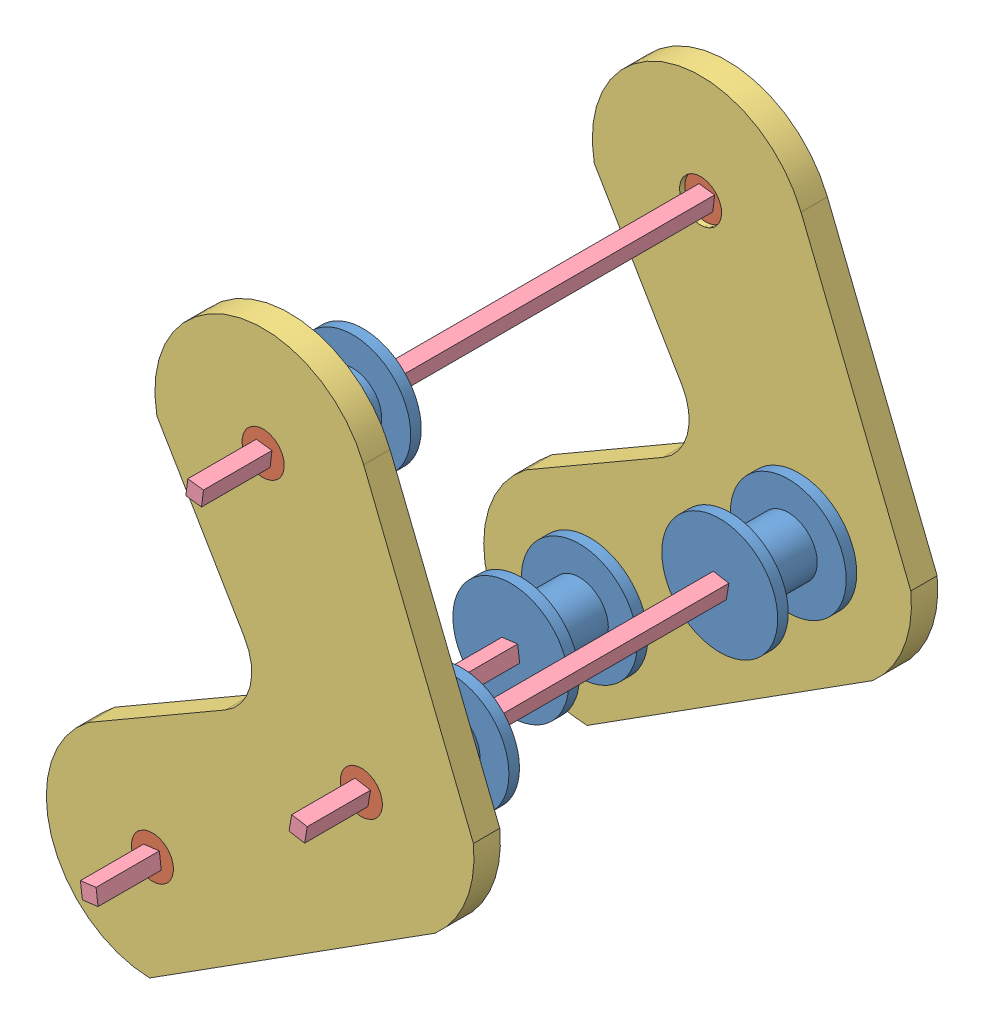
SolidWorks assembly intaker_assemble_new_20241129, configuration 默认. Lengths in mm.
Overall size (105.46 125.93 101).
15 component instances, 4 part files, 37 mates.
Components (placement in the parent):
- pulley_metal_20241129-1: pulley_metal_20241129 [默认] at (-0.8886 -0.165 14.4853) size (21.99 21.99 15)
- falon_metal_20241129-1: falon_metal_20241129 [默认] at (-0.8886 -0.165 29.4853) x (0.992516 -0.122117 0) z (0 0 1) size (8 8 4)
- intaker_sidewall_acrylic_4mm_20241129-1: intaker_sidewall_acrylic_4mm_20241129 [默认] at (-71.4861 23.1368 28.4853) x (0.186856 -0.982387 0) z (0 0 1) size (111.81 86.08 5)
- intaker_sticker_metal_20241129-1: intaker_sticker_metal_20241129 [默认] at (-2.5606 -1.4706 -53.5147) x (0.992516 -0.122117 0) z (0 0 1) size (3 3 100)
- intaker_sticker_metal_20241129-2: intaker_sticker_metal_20241129 [默认] at (19.481 -45.3327 -54.5147) x (-0.985911 0.167272 0) z (0 0 1) size (3 3 100)
- falon_metal_20241129-2: falon_metal_20241129 [默认] at (17.7512 -46.5607 29.4853) x (-0.985911 0.167272 0) z (0 0 1) size (8 8 4)
- pulley_metal_20241129-2: pulley_metal_20241129 [默认] at (17.7512 -46.5607 14.4853) size (21.99 21.99 15)
- intaker_sticker_metal_20241129-3: intaker_sticker_metal_20241129 [默认] at (-23.5728 -75.7235 -54.5147) x (0.125046 -0.992151 0) z (0 0 1) size (3 3 100)
- falon_metal_20241129-3: falon_metal_20241129 [默认] at (-21.897 -77.0241 29.4853) x (0.125046 -0.992151 0) z (0 0 1) size (8 8 4)
- intaker_sidewall_acrylic_4mm_20241129-2: intaker_sidewall_acrylic_4mm_20241129 [默认] at (-71.4861 23.1368 -54.5147) x (0.186856 -0.982387 0) z (0 0 1) size (111.81 86.08 5)
- pulley_metal_20241129-4: pulley_metal_20241129 [默认] at (-21.897 -77.0241 -49.5147) x (0.125046 -0.992151 0) z (0 0 1) size (21.99 21.99 15)
- pulley_metal_20241129-5: pulley_metal_20241129 [默认] at (17.7512 -46.5607 -49.5147) x (-0.167272 -0.985911 0) z (0 0 1) size (21.99 21.99 15)
- falon_metal_20241129-4: falon_metal_20241129 [默认] at (17.7512 -46.5607 -54.5147) x (-0.167272 -0.985911 0) z (0 0 1) size (8 8 4)
- falon_metal_20241129-5: falon_metal_20241129 [默认] at (-0.8886 -0.165 -54.5147) x (0.992516 -0.122117 0) z (0 0 1) size (8 8 4)
- falon_metal_20241129-6: falon_metal_20241129 [默认] at (-21.897 -77.0241 -54.5147) size (8 8 4)
Mates (geometry in assembly coordinates):
- 同心1: concentric aligned: cylinder of falon_metal_20241129-1 through (-0.8886 -0.165 33.4853) axis (0 0 -1) radius 4; cylinder of intaker_sidewall_acrylic_4mm_20241129-1 through (-0.8886 -0.165 33.4853) axis (0 0 -1) radius 4
- 重合1: coincident aligned: plane of falon_metal_20241129-1 through (-0.8886 -0.165 33.4853) normal (0 0 1); plane of intaker_sidewall_acrylic_4mm_20241129-1 through (-71.4861 23.1368 33.4853) normal (0 0 1)
- 重合4: coincident anti-aligned: plane of pulley_metal_20241129-1 through (-0.8886 -0.165 29.4853) normal (0 0 1); plane of falon_metal_20241129-1 through (-0.8886 -0.165 29.4853) normal (0 0 -1)
- 同心2: concentric aligned: circle of pulley_metal_20241129-1; circle of falon_metal_20241129-1
- 重合7: coincident anti-aligned: plane of falon_metal_20241129-1 through (-2.5606 -1.4706 33.4853) normal (0.122117 0.992516 0); plane of intaker_sticker_metal_20241129-1 through (-2.5606 -1.4706 46.4853) normal (-0.122117 -0.992516 0)
- 重合8: coincident anti-aligned: plane of falon_metal_20241129-1 through (-2.5606 -1.4706 33.4853) normal (0.992516 -0.122117 0); plane of intaker_sticker_metal_20241129-1 through (-2.5606 -1.4706 46.4853) normal (-0.992516 0.122117 0)
- 距离1: distance = 13 mm aligned: plane of intaker_sticker_metal_20241129-1 through (-2.5606 -1.4706 46.4853) normal (0 0 1); plane of intaker_sidewall_acrylic_4mm_20241129-1 through (-71.4861 23.1368 33.4853) normal (0 0 1)
- 重合10: coincident anti-aligned: plane of falon_metal_20241129-2 through (17.7512 -46.5607 29.4853) normal (0 0 -1); plane of pulley_metal_20241129-2 through (17.7512 -46.5607 29.4853) normal (0 0 1)
- 重合11: coincident anti-aligned: plane of intaker_sticker_metal_20241129-2 through (19.481 -45.3327 45.4853) normal (0.985911 -0.167272 0); plane of falon_metal_20241129-2 through (19.481 -45.3327 33.4853) normal (-0.985911 0.167272 0)
- 重合12: coincident anti-aligned: plane of intaker_sticker_metal_20241129-2 through (19.481 -45.3327 45.4853) normal (0.167272 0.985911 0); plane of falon_metal_20241129-2 through (19.481 -45.3327 33.4853) normal (-0.167272 -0.985911 0)
- 同心3: concentric aligned: circle of falon_metal_20241129-2; circle of pulley_metal_20241129-2
- 重合13: coincident aligned: circle of intaker_sidewall_acrylic_4mm_20241129-1; circle of falon_metal_20241129-2
- 距离2: distance = 12 mm aligned: plane of intaker_sticker_metal_20241129-2 through (19.481 -45.3327 45.4853) normal (0 0 1); plane of falon_metal_20241129-2 through (17.7512 -46.5607 33.4853) normal (0 0 1)
- 重合15: coincident anti-aligned: plane of pulley_metal_20241129-3 through (72.0609 -32.2125 29.4853) normal (0 0 1); plane of falon_metal_20241129-3 through (-21.897 -77.0241 29.4853) normal (0 0 -1)
- 重合16: coincident anti-aligned: plane of intaker_sticker_metal_20241129-3 through (-23.5728 -75.7235 45.4853) normal (-0.125046 0.992151 0); plane of falon_metal_20241129-3 through (-23.5728 -75.7235 33.4853) normal (0.125046 -0.992151 0)
- 重合17: coincident anti-aligned: plane of intaker_sticker_metal_20241129-3 through (-23.5728 -75.7235 45.4853) normal (-0.992151 -0.125046 0); plane of falon_metal_20241129-3 through (-23.5728 -75.7235 33.4853) normal (0.992151 0.125046 0)
- 同心4: concentric aligned: circle of pulley_metal_20241129-3; circle of falon_metal_20241129-3
- 重合18: coincident aligned: circle of intaker_sidewall_acrylic_4mm_20241129-1; circle of falon_metal_20241129-3
- 距离3: distance = 12 mm aligned: plane of intaker_sticker_metal_20241129-3 through (-23.5728 -75.7235 45.4853) normal (0 0 1); plane of intaker_sidewall_acrylic_4mm_20241129-1 through (-71.4861 23.1368 33.4853) normal (0 0 1)
- 同心5: concentric aligned: cylinder of intaker_sidewall_acrylic_4mm_20241129-2 through (17.7512 -46.5607 -49.5147) axis (0 0 -1) radius 4; cylinder of falon_metal_20241129-4 through (17.7512 -46.5607 -50.5147) axis (0 0 -1) radius 4
- 重合20: coincident aligned: plane of intaker_sidewall_acrylic_4mm_20241129-2 through (-71.4861 23.1368 -54.5147) normal (0 0 -1); plane of falon_metal_20241129-4 through (17.7512 -46.5607 -54.5147) normal (0 0 -1)
- 同心6: concentric aligned: cylinder of intaker_sidewall_acrylic_4mm_20241129-2 through (-21.897 -77.0241 -49.5147) axis (0 0 -1) radius 4; cylinder of falon_metal_20241129-6 through (-21.897 -77.0241 -50.5147) axis (0 0 -1) radius 4
- 重合21: coincident aligned: plane of intaker_sidewall_acrylic_4mm_20241129-2 through (-71.4861 23.1368 -54.5147) normal (0 0 -1); plane of falon_metal_20241129-6 through (-21.897 -77.0241 -54.5147) normal (0 0 -1)
- 同心7: concentric aligned: cylinder of intaker_sidewall_acrylic_4mm_20241129-2 through (-0.8886 -0.165 -49.5147) axis (0 0 -1) radius 4; cylinder of falon_metal_20241129-5 through (-0.8886 -0.165 -50.5147) axis (0 0 -1) radius 4
- 重合22: coincident aligned: plane of intaker_sidewall_acrylic_4mm_20241129-2 through (-71.4861 23.1368 -54.5147) normal (0 0 -1); plane of falon_metal_20241129-5 through (-0.8886 -0.165 -54.5147) normal (0 0 -1)
- 重合23: coincident anti-aligned: plane of intaker_sticker_metal_20241129-3 through (-23.1977 -78.6999 45.4853) normal (0.125046 -0.992151 0); plane of pulley_metal_20241129-4 through (-23.1977 -78.6999 -47.5147) normal (-0.125046 0.992151 0)
- 重合24: coincident anti-aligned: plane of intaker_sticker_metal_20241129-3 through (-20.5964 -75.3483 45.4853) normal (0.992151 0.125046 0); plane of pulley_metal_20241129-4 through (-20.5964 -75.3483 -47.5147) normal (-0.992151 -0.125046 0)
- 重合25: coincident anti-aligned: plane of intaker_sidewall_acrylic_4mm_20241129-2 through (-71.4861 23.1368 -49.5147) normal (0 0 1); plane of pulley_metal_20241129-4 through (-21.897 -77.0241 -49.5147) normal (0 0 -1)
- 同心8: concentric aligned: circle of intaker_sidewall_acrylic_4mm_20241129-2; circle of pulley_metal_20241129-4
- 重合26: coincident anti-aligned: plane of intaker_sticker_metal_20241129-2 through (19.481 -45.3327 45.4853) normal (0.167272 0.985911 0); plane of pulley_metal_20241129-5 through (16.5232 -44.8309 -47.5147) normal (-0.167272 -0.985911 0)
- 重合27: coincident anti-aligned: plane of intaker_sticker_metal_20241129-2 through (19.481 -45.3327 45.4853) normal (0.985911 -0.167272 0); plane of pulley_metal_20241129-5 through (19.481 -45.3327 -47.5147) normal (-0.985911 0.167272 0)
- 重合28: coincident anti-aligned: plane of intaker_sidewall_acrylic_4mm_20241129-2 through (-71.4861 23.1368 -49.5147) normal (0 0 1); plane of pulley_metal_20241129-5 through (17.7512 -46.5607 -49.5147) normal (0 0 -1)
- 重合29: coincident anti-aligned: plane of intaker_sticker_metal_20241129-2 through (19.481 -45.3327 45.4853) normal (0.167272 0.985911 0); plane of falon_metal_20241129-4 through (16.5232 -44.8309 -50.5147) normal (-0.167272 -0.985911 0)
- 重合31: coincident aligned: plane of intaker_sticker_metal_20241129-2 through (19.481 -45.3327 -54.5147) normal (0 0 -1); plane of intaker_sidewall_acrylic_4mm_20241129-2 through (-71.4861 23.1368 -54.5147) normal (0 0 -1)
- 重合32: coincident anti-aligned: plane of intaker_sticker_metal_20241129-1 through (-2.1942 1.5069 46.4853) normal (0.122117 0.992516 0); plane of falon_metal_20241129-5 through (-2.1942 1.5069 -50.5147) normal (-0.122117 -0.992516 0)
- 重合33: coincident anti-aligned: plane of intaker_sticker_metal_20241129-1 through (-2.5606 -1.4706 46.4853) normal (-0.992516 0.122117 0); plane of falon_metal_20241129-5 through (-2.5606 -1.4706 -50.5147) normal (0.992516 -0.122117 0)
- 平行1: parallel aligned: plane of intaker_sticker_metal_20241129-3 through (-23.5728 -75.7235 -54.5147) normal (0 0 -1); plane of intaker_sidewall_acrylic_4mm_20241129-2 through (-71.4861 23.1368 -54.5147) normal (0 0 -1)
